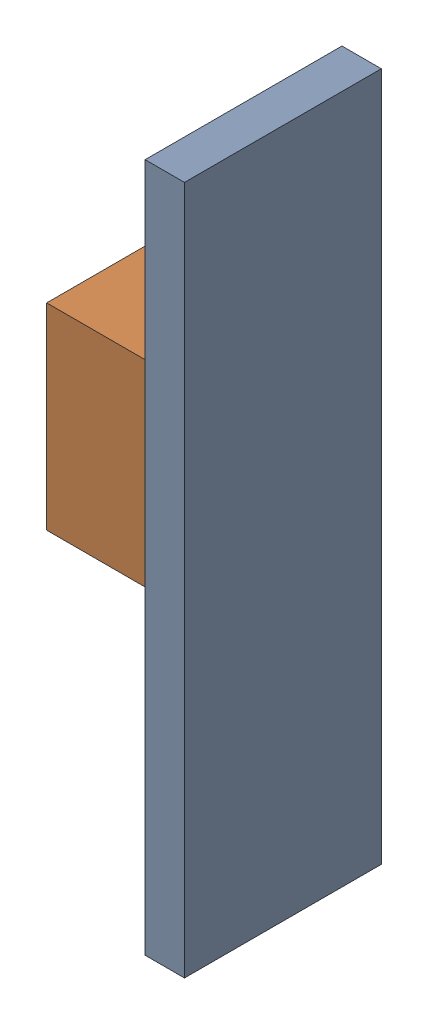
SolidWorks assembly _1, configuration Default. Lengths in mm.
Overall size (8.89 44.45 12.7).
4 component instances, 2 part files, 0 mates.
Components (placement in the parent):
- 402658832-1: 402658832 [Default] at (13.7414 80.2386 0) size (2.54 44.45 12.7)
  - Extruded-1: Extruded [Default] at origin size (2.54 44.45 12.7)
- 402658704-1: 402658704 [Default] at (9.2964 84.9376 1.27) size (6.35 12.7 11.43)
  - Extruded_1-1: Extruded_1 [Default] at origin size (6.35 12.7 11.43)
